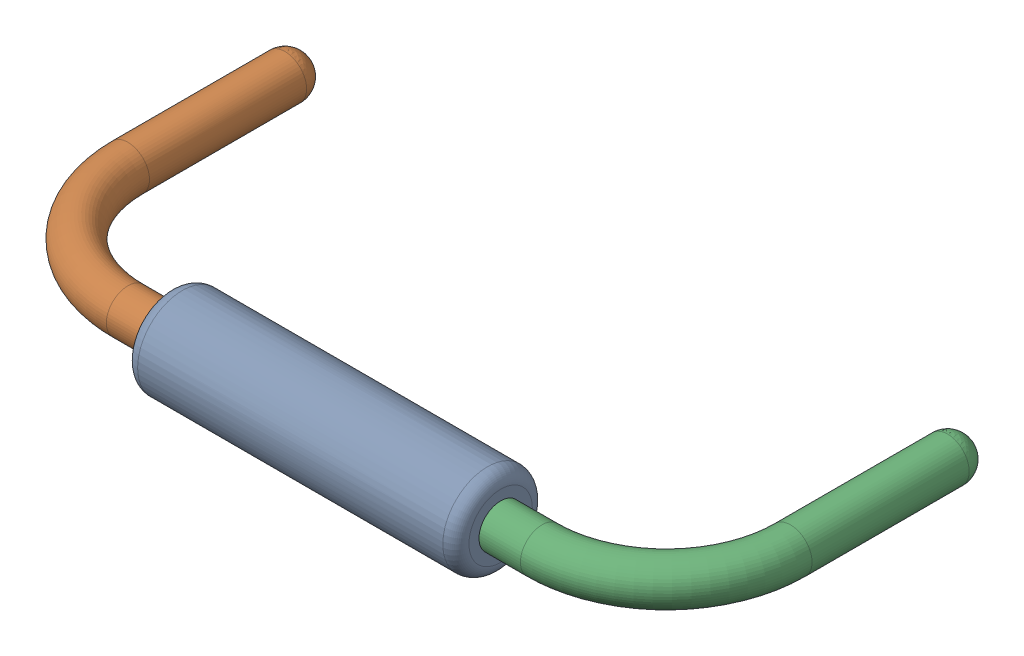
SolidWorks assembly Open CASCADE STEP translator 6.8 1.10.1, configuration Défaut. Lengths in mm.
Overall size (10.82 1.37 5.33).
3 component instances, 3 part files, 0 mates.
Components (placement in the parent):
- Body_1_7-1: Body_1_7 [Défaut] at origin size (5.08 1.37 1.37)
- Pin_1_4-1: Pin_1_4 [Défaut] at origin size (3.2 0.66 4.98)
- Pin_2_4-1: Pin_2_4 [Défaut] at (20.32 0 0) x (-1 0 0) z (0 0 1) size (3.2 0.66 4.98)
